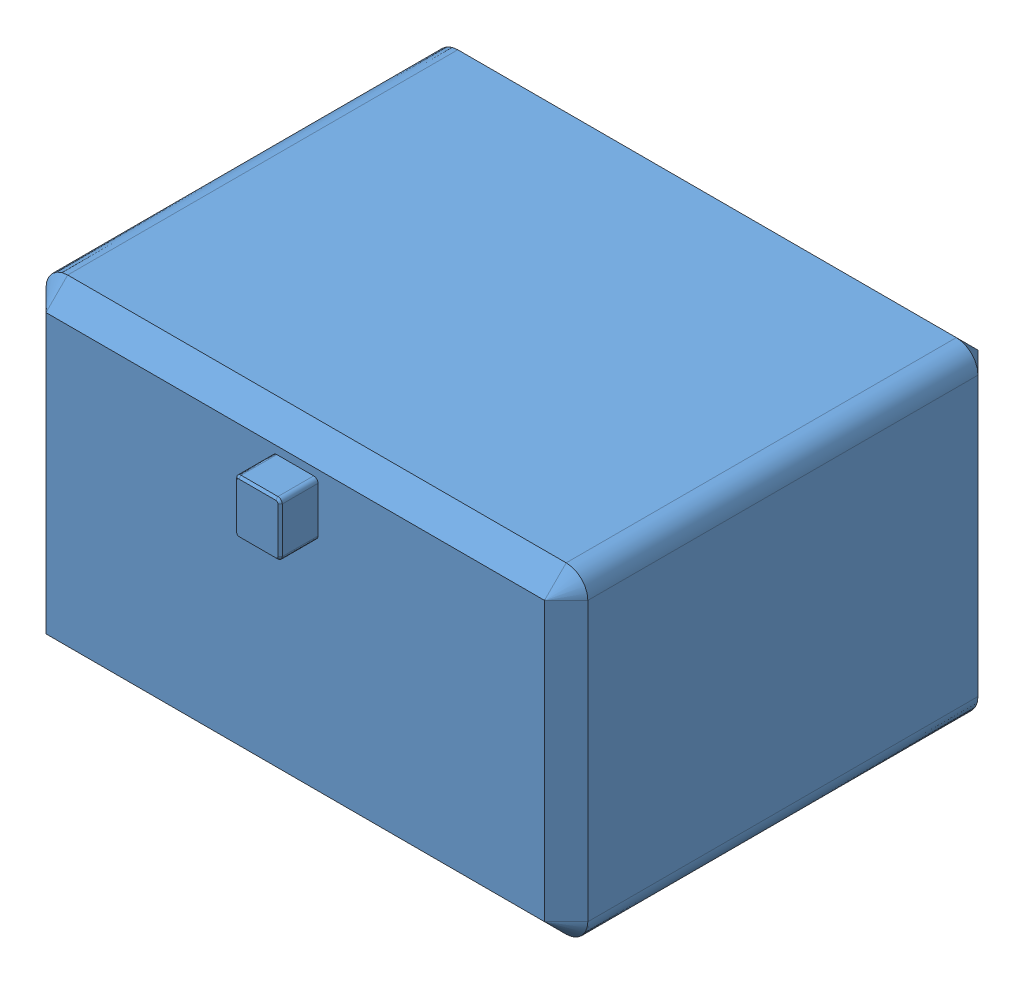
SolidWorks assembly release_button_jig, configuration Default. Lengths in mm.
Overall size (25 14.84 21.75).
2 component instances, 2 part files, 4 mates.
Components (placement in the parent):
- release_button-1: release_button [Default] at (-15.8039 -20.9788 17.4153) size (12.7 15.24 12.7) (hidden)
- release_button_jig-1: release_button_jig [Default] at (-15.8039 -20.9788 11.0653) x (-1 0 0) z (0 0 -1) size (25 14.84 21.75)
Mates (geometry in assembly coordinates):
- InPlace1: in place: plane of release_button-1 through (-15.8039 -20.9788 11.0653) normal (0 0 -1); plane of release_button_jig-1 through (-15.8039 -20.9788 11.0653) normal (0 0 -1); moOrthogonalPlaneRef_w of release_button-1 through (-15.8039 -20.9788 11.0653) normal (0 0 -1); unknown of release_button_jig-1; plane of release_button-1 through (-15.8039 -20.9788 11.0653) normal (0 0 -1); plane of release_button_jig-1 through (-15.8039 -20.9788 11.0653) normal (-1 0 0); plane of release_button-1 through (-15.8039 -20.9788 11.0653) normal (0 0 -1); unknown of release_button_jig-1
- Coincident1: coincident aligned: plane of release_button-1; plane of release_button_jig-1
- Coincident2: coincident aligned: moOrthogonalPlaneRef_w of release_button-1; plane of release_button_jig-1
- Coincident3: coincident anti-aligned: moOrthogonalPlaneRef_w of release_button-1; plane of release_button_jig-1 through (-15.8039 -20.9788 11.0653) normal (-1 0 0)
